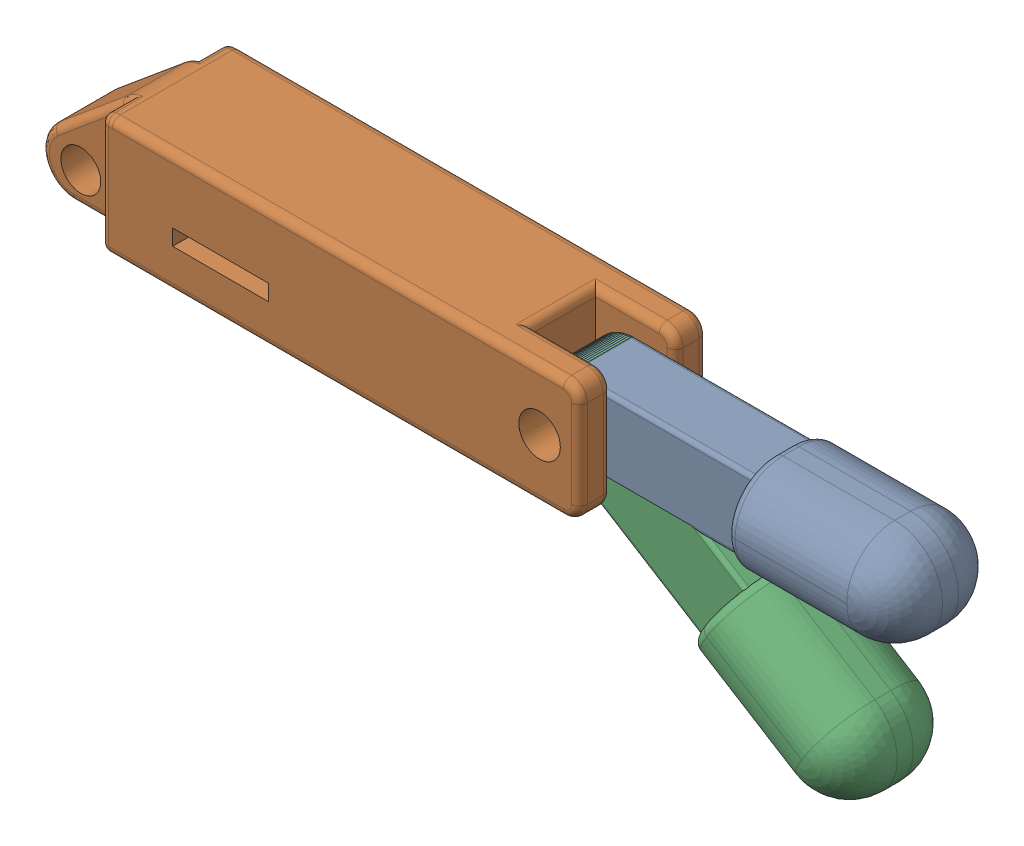
SolidWorks assembly Joint Finger assem, configuration Default. Lengths in mm.
Overall size (106.26 35.7 16).
2 component instances, 2 part files, 7 mates.
Components (placement in the parent):
- Joint finger-1: Joint finger [Default] at origin size (109.65 15.32 16)
- Joint finger_top-1: Joint finger_top [Default] at (4.3356 30.1796 0) x (0.849151 -0.52815 0) z (0 0 1) size (48.3 12 14)
Mates (geometry in assembly coordinates):
- Concentric1: concentric aligned: cylinder of Joint finger-1 through (55 7.5 0) axis (0 0 1) radius 2.6; cylinder of Joint finger_top-1 through (55 7.5 0) axis (0 0 1) radius 2.6
- Coincident1: coincident anti-aligned: plane of Joint finger-1 through (50 -0.001 12) normal (0 0 -1); plane of Joint finger_top-1 through (4.3356 30.1796 12) normal (0 0 1)
- LimitAngle1: limit planar angle = 0.556421 rad aligned: plane of Joint finger-1 through (0 15 16) normal (0 1 0); plane of Joint finger_top-1 through (10.8318 40.6242 12) normal (0.52815 0.849151 0)
- Coincident6: coincident anti-aligned: plane of Joint finger-1 through (0 0 16) normal (0 0 1); plane of 91290A248_Alloy Steel Socket Head Screw-1 through (55 11.5 16) normal (0 0 -1)
- Concentric6: concentric anti-aligned: cylinder of Joint finger-1 through (55 7.5 0) axis (0 0 1) radius 2.6; cylinder of 91290A248_Alloy Steel Socket Head Screw-1 through (55 7.5 -6) axis (0 0 -1) radius 4.25
- Coincident7: coincident anti-aligned: plane of Joint finger-1 through (0 0 0) normal (0 0 -1); plane of 90685A041_High-Strength Steel Hex Nut-1 through (55 7.5 0) normal (0 0 1)
- Concentric7: concentric aligned: cylinder of 91290A248_Alloy Steel Socket Head Screw-1 through (55 7.5 -6) axis (0 0 -1) radius 2.5; cylinder of 90685A041_High-Strength Steel Hex Nut-1 through (55 7.5 0) axis (0 0 -1) radius 2.5
